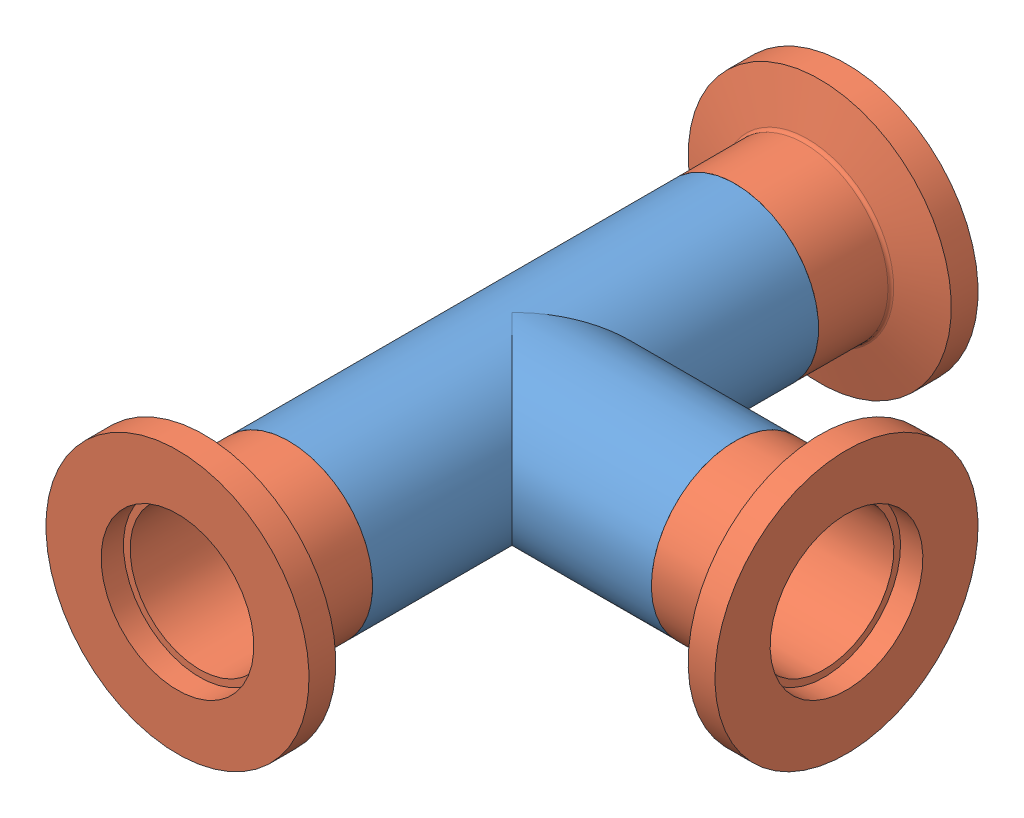
SolidWorks assembly 724000, configuration Default. Lengths in mm.
Overall size (57.76 39.32 76.2).
4 component instances, 2 part files, 4 mates.
Components (placement in the parent):
- 404500-1: 404500 [Default] at (17.7635 27.5918 34.7026) size (34.92 19.05 50.8)
- 713001-1: 713001 [Default] at (17.7635 27.5918 72.8026) x (0.920066 0.391763 0) z (0 0 -1) size (29.97 29.97 14.22)
- 713001-2: 713001 [Default] at (17.7635 27.5918 -3.3974) x (0.99882 0.04857 0) z (0 0 1) size (29.97 29.97 14.22)
- 713001-3: 713001 [Default] at (55.8635 27.5918 34.7026) x (0 0.034426 -0.999407) z (-1 0 0) size (29.97 29.97 14.22)
Mates (geometry in assembly coordinates):
- Concentric1: concentric aligned: cylinder of 404500-1 through (17.7635 27.5918 60.1026) axis (0 0 -1) radius 9.525; circle of 713001-1
- Coincident1: coincident anti-aligned: plane of 404500-1 through (17.7635 27.5918 60.1026) normal (0 0 1); plane of 713001-1 through (25.5924 30.9253 60.1026) normal (0 0 -1)
- Coincident2: coincident anti-aligned: circle of 404500-1; circle of 713001-2
- Coincident6: coincident aligned: circle of 404500-1; circle of 713001-3
